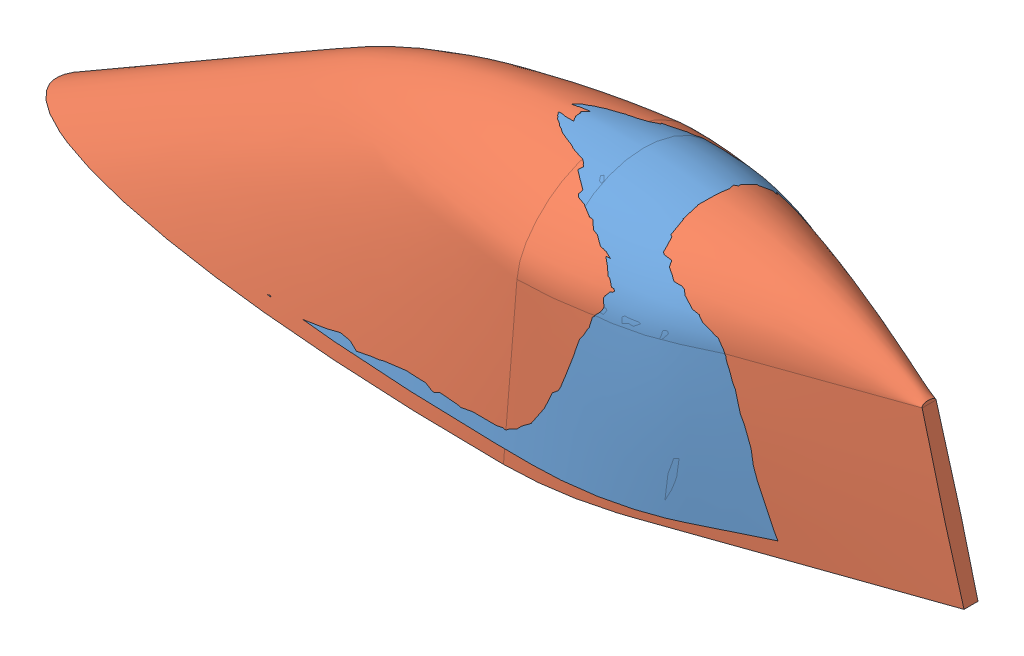
SolidWorks assembly Canopy4and4-2, configuration Default. Lengths in mm.
Overall size (1696.54 425.83 575.69).
2 component instances, 2 part files, 4 mates.
Components (placement in the parent):
- windshileld4-1: windshileld4 [Default] at origin size (1688.13 400.44 575.69)
- windshileld4-2-1: windshileld4-2 [Default] at (-52.2172 -25.4 0) size (1663.73 419.26 406.43)
Mates (geometry in assembly coordinates):
- Coincident1: coincident: plane of windshileld4-1 through (0 0 0) normal (0 0 1); plane of assembly through (0 0 0) normal (0 0 1)
- Coincident2: coincident aligned: plane of windshileld4-2-1 through (-52.2172 -25.4 0) normal (0 0 1)
- Distance1: distance = 25.4 mm: plane of assembly through (0 0 0) normal (0 1 0); plane of assembly; plane of windshileld4-2-1 through (-52.2172 -25.4 0) normal (0 1 0)
- Coincident4: coincident: plane of windshileld4-1 through (0 0 0) normal (0 1 0); plane of assembly through (0 0 0) normal (0 1 0)
